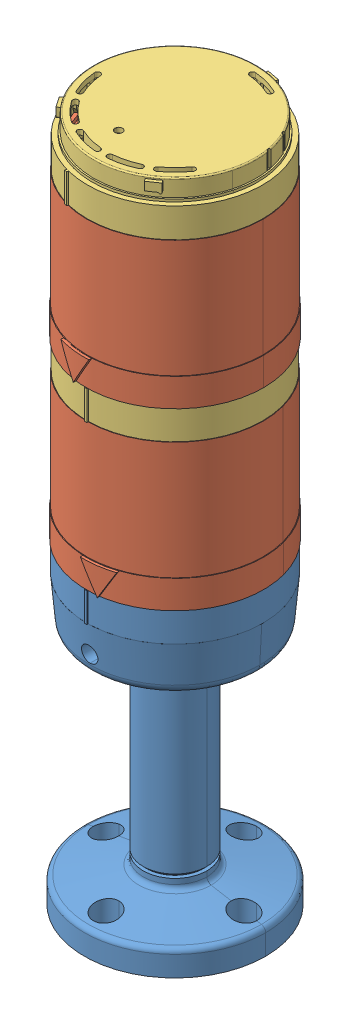
SolidWorks assembly StackLight_Assembly, configuration Red. Lengths in mm.
Overall size (103.25 272.82 103.6).
9 component instances, 3 part files, 9 mates.
Components (placement in the parent):
- 855t-bpm10-1: 855t-bpm10 [Default] at origin
- 855t_module-1: 855t_module [Red] at (0 98.5 0) size (84.2 76.26 84.69)
  - 855t_module(2)^855t_module-1: 855t_module(2)^855t_module [Red] at origin size (84.2 76.26 84.69) (virtual)
    - 40378-011^855t_module(2)_855t_module-1: 40378-011^855t_module(2)_855t_module [default red] at origin size (69.5 65.01 72.38) (virtual)
    - 40378-007^855t_module(2)_855t_module-1: 40378-007^855t_module(2)_855t_module [Default] at (0 57 0) x (0.965926 0 0.258819) z (-0.258819 0 0.965926) (virtual)
- 855t_module-2: 855t_module [Red] at (0 30 0) x (0.965926 0 -0.258819) z (0.258819 0 0.965926) size (84.2 76.26 84.69)
  - 855t_module(2)^855t_module-1: 855t_module(2)^855t_module [Red] at origin size (84.2 76.26 84.69) (virtual)
    - 40378-011^855t_module(2)_855t_module-1: 40378-011^855t_module(2)_855t_module [default red] at origin size (69.5 65.01 72.38) (virtual)
    - 40378-007^855t_module(2)_855t_module-1: 40378-007^855t_module(2)_855t_module [Default] at (0 57 0) x (0.965926 0 0.258819) z (-0.258819 0 0.965926) (virtual)
Mates (geometry in assembly coordinates):
- Concentric2: concentric anti-aligned: cylinder of 855t_module-1/855t_module(2)^855t_module-1/40378-007^855t_module(2)_855t_module-1 through (0 168.05 0) axis (0 -1 0) radius 32.4; cylinder of 855t_module-2/855t_module(2)^855t_module-1/40378-011^855t_module(2)_855t_module-1 through (0 29.92 0) axis (0 1 0) radius 33.75
- Coincident2: coincident anti-aligned: plane of 855t_module-1/855t_module(2)^855t_module-1/40378-011^855t_module(2)_855t_module-1 through (0 98.5 0) normal (0 -1 0); plane of 855t_module-2/855t_module(2)^855t_module-1/40378-007^855t_module(2)_855t_module-1 through (0 98.5 0) normal (0 1 0)
- Coincident3: coincident anti-aligned: plane of 855t-bpm10-1 through (0 30 0) normal (0 1 0); plane of 855t_module-2/855t_module(2)^855t_module-1/40378-011^855t_module(2)_855t_module-1 through (0 30 0) normal (0 -1 0)
- Coincident4: coincident aligned: plane of 855t-bpm10-1 through (0 0 0) normal (0 0 1)
- Coincident5: coincident aligned: plane of 855t-bpm10-1 through (0 0 0) normal (0 1 0)
- Coincident6: coincident aligned: plane of 855t-bpm10-1 through (0 0 0) normal (1 0 0)
- Coincident7: coincident aligned: plane of 855t_module-1 through (0 98.5 0) normal (0 0 1)
- Coincident8: coincident aligned: plane of 855t_module-1 through (0 98.5 0) normal (1 0 0)
- Coincident9: coincident aligned: plane of 855t-bpm10-1 through (0.5 18.5 35) normal (1 0 0); plane of 855t_module-2/855t_module(2)^855t_module-1/40378-007^855t_module(2)_855t_module-1 through (0.5 87 35) normal (1 0 0)
